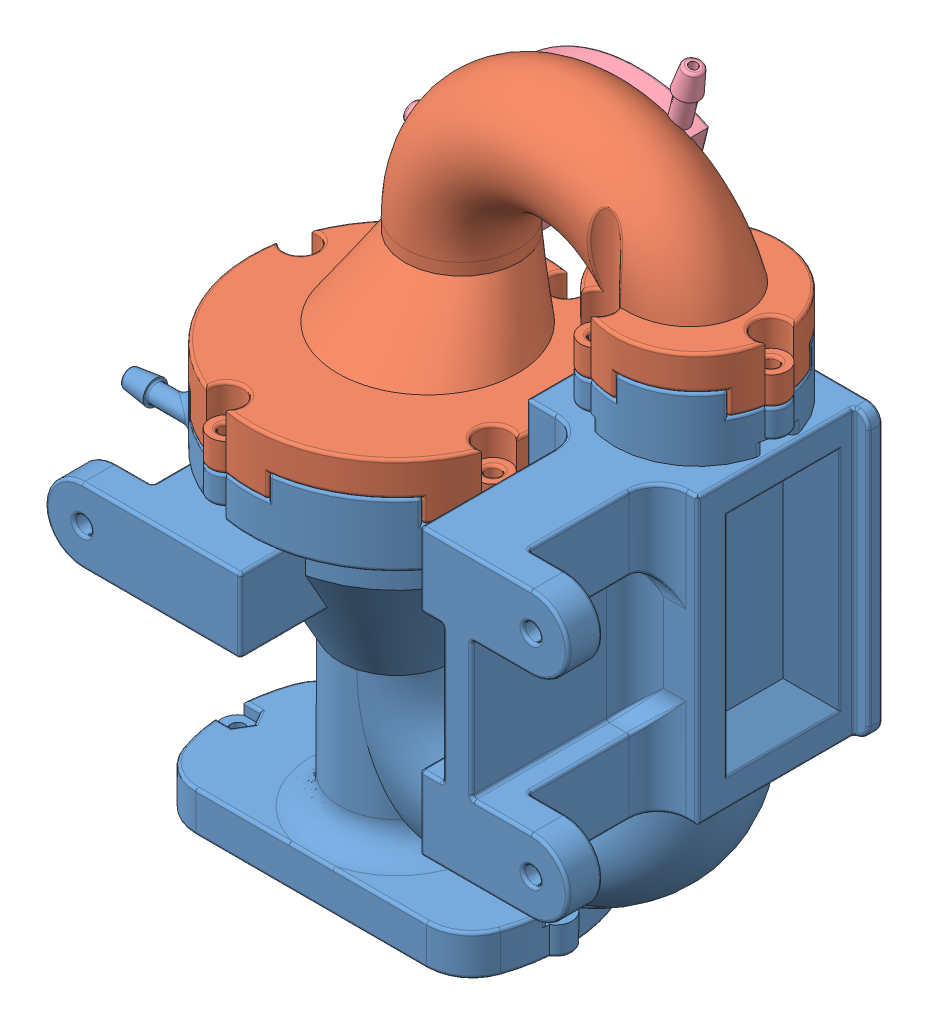
SolidWorks assembly CoolingAss, configuration Default. Lengths in mm.
Overall size (93.6 126.87 58.74).
7 component instances, 4 part files, 19 mates.
Components (placement in the parent):
- Water Tunnel-1: Water Tunnel [Default] at origin size (93.6 95.13 58.74)
- U Tube-1: U Tube [Default] at (0 9 0) x (1 0 0) z (0 1 0) size (83.46 52.58 53.84)
- SMD Cooler 8x8x6mm-1: SMD Cooler 8x8x6mm [Default] at (-41.4 32.1 8) x (-0.981152 0.193237 0) z (0.193237 0.981152 0) size (8 6 8)
- SMD Cooler 8x8x6mm-2: SMD Cooler 8x8x6mm [Default] at (-38.4486 42.7526 8) x (-0.741815 0.670605 0) z (0.670605 0.741815 0) size (8 6 8)
- SMD Cooler 8x8x6mm-3: SMD Cooler 8x8x6mm [Default] at (-30.4359 50.3675 8) x (-0.290939 0.956742 0) z (0.956742 0.290939 0) size (8 6 8)
- SMD Cooler 8x8x6mm-4: SMD Cooler 8x8x6mm [Default] at (-11.8865 50.83 8) x (-0.242901 -0.970051 0) z (-0.970051 0.242901 0) size (8 6 8)
- Cooling Tube Top-1: Cooling Tube Top [Default] at (0 9 8) x (1 0 0) z (0 0 -1) size (51.23 38.97 4.94)
Mates (geometry in assembly coordinates):
- Coincident1: coordinate: point of Water Tunnel-1
- Coincident2: coincident anti-aligned: plane of Water Tunnel-1 through (0 9 0) normal (0 1 0); plane of U Tube-1 through (-41.4 9 26.4) normal (0 -1 0)
- Concentric1: concentric anti-aligned: cylinder of Water Tunnel-1 through (-41.4 -4 26.4) axis (0 1 0) radius 16.4; cylinder of U Tube-1 through (-41.4 14 26.4) axis (0 -1 0) radius 25.8513
- Parallel1: parallel anti-aligned: plane of Water Tunnel-1 through (0 36.1 0) normal (-1 0 0); plane of U Tube-1 through (0 36.1 0) normal (1 0 0)
- Coincident4: coincident: plane of U Tube-1 through (-18.6753 56.6534 0.1088) normal (0.970051 -0.242901 0); plane of SMD Cooler 8x8x6mm-4 through (-19.6469 52.7732 8) normal (-0.970051 0.242901 0)
- Coincident5: coincident: plane of U Tube-1 through (-20.6185 48.893 0.1088) normal (0.242901 0.970051 0); plane of SMD Cooler 8x8x6mm-4 through (-20.6185 48.893 8) normal (-0.242901 -0.970051 0)
- Coincident6: coincident: plane of U Tube-1 through (-29.2721 46.5406 0.1088) normal (-0.290939 0.956742 0); plane of SMD Cooler 8x8x6mm-3 through (-21.6182 48.8681 8) normal (0.290939 -0.956742 0)
- Coincident7: coincident: plane of U Tube-1 through (-31.5997 54.1945 0.1088) normal (0.956742 0.290939 0); plane of SMD Cooler 8x8x6mm-3 through (-30.4359 50.3675 8) normal (-0.956742 -0.290939 0)
- Coincident8: coincident: plane of U Tube-1 through (-35.4813 40.0702 0.1088) normal (-0.741815 0.670605 0); plane of SMD Cooler 8x8x6mm-2 through (-30.1165 46.0047 8) normal (0.741815 -0.670605 0)
- Coincident9: coincident: plane of U Tube-1 through (-41.4158 45.435 0.1088) normal (0.670605 0.741815 0); plane of SMD Cooler 8x8x6mm-2 through (-38.4486 42.7526 8) normal (-0.670605 -0.741815 0)
- Coincident10: coincident: plane of U Tube-1 through (-37.4754 31.3271 0.1088) normal (-0.981152 0.193237 0); plane of SMD Cooler 8x8x6mm-1 through (-35.9295 39.1763 8) normal (0.981152 -0.193237 0)
- Coincident11: coincident: plane of U Tube-1 through (-45.3246 32.8729 0.1088) normal (0.193237 0.981152 0); plane of SMD Cooler 8x8x6mm-1 through (-41.4 32.1 8) normal (-0.193237 -0.981152 0)
- Coincident12: coincident aligned: plane of U Tube-1 through (0 9 8) normal (0 0 -1); plane of SMD Cooler 8x8x6mm-1 through (-35.9295 39.1763 8) normal (0 0 -1)
- Coincident13: coincident aligned: plane of U Tube-1 through (0 9 8) normal (0 0 -1); plane of SMD Cooler 8x8x6mm-2 through (-30.1165 46.0047 8) normal (0 0 -1)
- Coincident14: coincident aligned: plane of U Tube-1 through (0 9 8) normal (0 0 -1); plane of SMD Cooler 8x8x6mm-3 through (-21.6182 48.8681 8) normal (0 0 -1)
- Coincident15: coincident aligned: plane of U Tube-1 through (0 9 8) normal (0 0 -1); plane of SMD Cooler 8x8x6mm-4 through (-18.6753 56.6534 8) normal (0 0 -1)
- Coincident16: coincident: plane of U Tube-1 through (0 9 8) normal (0 0 -1); plane of Cooling Tube Top-1 through (-20.7 32.1 8) normal (0 0 1)
- Concentric2: concentric: cylinder of U Tube-1 through (-20.7 32.1 94.0857) axis (0 0 -1) radius 14.3098; cylinder of Cooling Tube Top-1 through (-20.7 32.1 6.5) axis (0 0 1) radius 14.3098
- Coincident17: coincident anti-aligned: plane of U Tube-1 through (-35.3399 28.868 94.0857) normal (0.193237 0.981152 0); plane of Cooling Tube Top-1 through (-48.5414 31.4681 6.5) normal (-0.193237 -0.981152 0)
